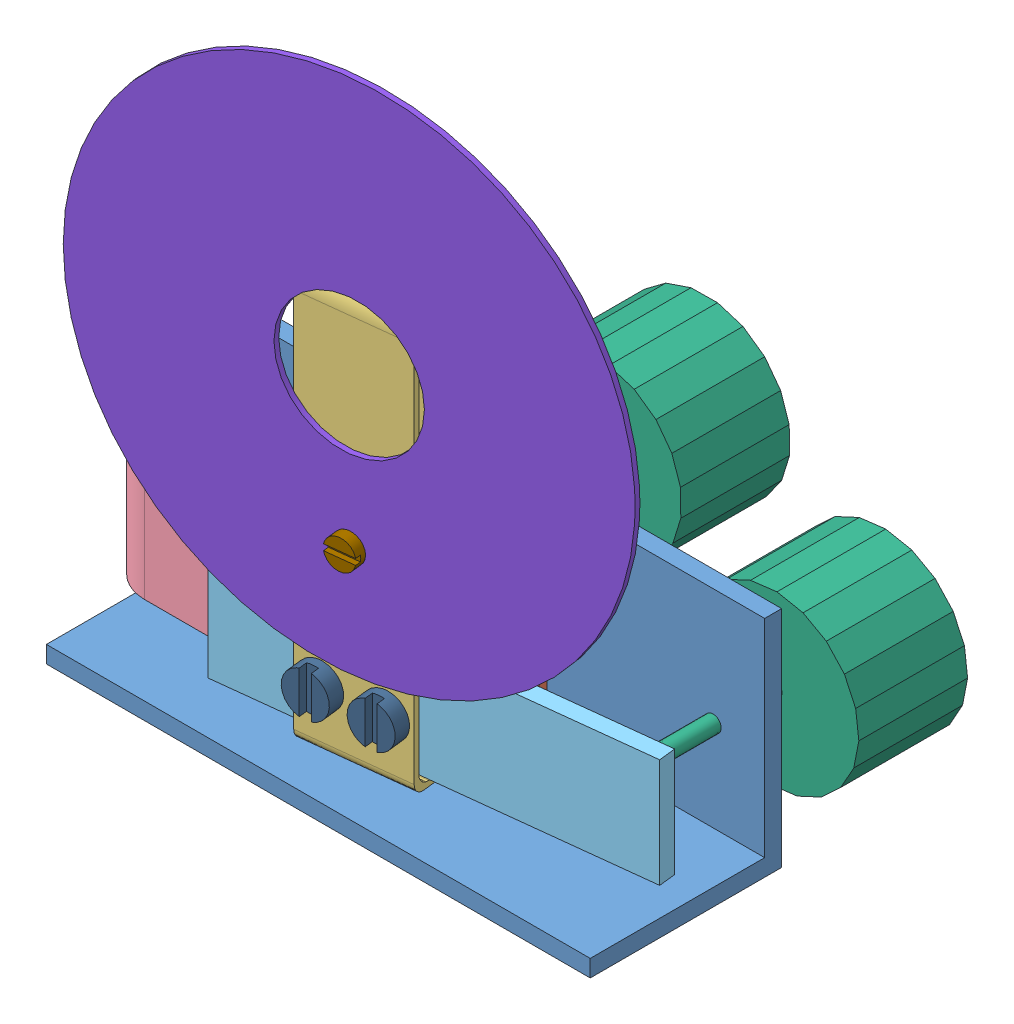
SolidWorks assembly Suporte do Hd, configuration Valor predeterminado. Lengths in mm.
Overall size (109.41 117.47 70.99).
25 component instances, 11 part files, 50 mates.
Components (placement in the parent):
- Base do divisor-1: Base do divisor [Default] at (-58.5949 -17.3298 117.599) size (100 41.23 35.2)
- Cantoneira pequena-2: Cantoneira pequena [Valor predeterminado] at (-18.5949 -13.8298 87.026) x (0 0 -1) z (1 0 0) size (16.5 16.5 20)
- Mola 1-1: Mola 1 [Valor predeterminado] at (-19.6607 -13.8298 89.0448) x (-0.113304 0 -0.99356) z (0.99356 0 -0.113304) size (25 80 20)
- Mola 2-1: Mola 2 [Valor predeterminado] at (-30.5949 8.7702 85.526) x (1 0 0) z (0 -1 0) size (30.12 25.83 20)
- Barra-1: Barra [Valor predeterminado] at (42.3181 -10.8298 102.9871) x (0.99356 0 -0.113304) z (0.113304 0 0.99356) size (75 20 3.12)
- Manipulo de tampinha de PET-1: Manipulo de tampinha de PET [Valor predeterminado] at (31.9104 -0.6809 54.3451) x (0.971217 0.238195 0) z (0 0 1) size (31.26 31.26 50)
- Manipulo de tampinha de PET-2: Manipulo de tampinha de PET [Valor predeterminado] at (-6.8829 13.8497 48.1396) x (0.879958 -0.475051 0) z (0 0 1) size (31.26 31.26 50)
- Porca M3-1: Porca M3 [Default] at (-6.8829 13.8497 94.3396) x (1 0 0) z (0 -1 0) size (6.52 3.8 6.82)
- HD-1: HD [Valor predeterminado] at (-6.8906 49.5081 112.7505) x (0.99356 -0.000072 -0.113304) z (0.113304 0 0.99356) size (95 95 1)
- Parafuso Padrao M3 10-1: Parafuso Padrao M3 10 [Default] at (-6.5526 22.0543 115.7314) x (-0.99356 0 0.113304) z (-0.113304 0 -0.99356) size (5.45 5.45 12)
- Porca M3-2: Porca M3 [Default] at (-7.0058 22.0543 111.7572) x (0.987162 0.113304 -0.112574) z (-0.112574 0.99356 0.012838) size (6.52 3.8 6.82)
- Parafuso Padrao M3 10-2: Parafuso Padrao M3 10 [Default] at (-16.0294 -6.3298 80.401) size (5.45 5.45 12)
- Parafuso Padrao M3 10-3: Parafuso Padrao M3 10 [Default] at (-1.1604 -6.3298 80.401) size (5.45 5.45 12)
- Porca M3-3: Porca M3 [Default] at (-16.0294 -6.3298 87.026) x (1 0 0) z (0 -1 0) size (6.52 3.8 6.82)
- Porca M3-4: Porca M3 [Default] at (-1.1604 -6.3298 87.026) x (1 0 0) z (0 -1 0) size (6.52 3.8 6.82)
- Parafuso Padrao M4-1: Parafuso Padrao M4 [Default] at (-40.5949 4.0287 82.401) x (-0.228935 0.973442 0) z (-0.973442 -0.228935 0) size (8 13 8)
- Parafuso Padrao M4-2: Parafuso Padrao M4 [Default] at (-40.5949 -7.6252 82.401) x (1 0 0) z (0 1 0) size (8 13 8)
- Parafuso Padrao M4-3: Parafuso Padrao M4 [Default] at (-12.557 -2.8298 113.3967) x (-0.99356 0 0.113304) z (0 1 0) size (8 13 8)
- Parafuso Padrao M4-4: Parafuso Padrao M4 [Default] at (-1.6819 -2.8298 112.1565) x (-0.99356 0 0.113304) z (0 1 0) size (8 13 8)
- Parafuso Padrao M4-5: Parafuso Padrao M4 [Default] at (-8.5921 -15.3298 97.8473) x (1 0 0) z (0 0 -1) size (8 13 8)
- Porca M4-1: Porca M4 [Default] at (-40.5949 4.0287 86.526) x (1 0 0) z (0 -1 0) size (7.78 3.12 8.95)
- Porca M4-2: Porca M4 [Default] at (-8.5921 -12.8298 97.8473) size (7.78 3.12 8.95)
- Porca M4-3: Porca M4 [Default] at (-13.3784 -2.8298 106.1934) x (0.987162 -0.113304 -0.112574) z (-0.112574 -0.99356 0.012838) size (7.78 3.12 8.95)
- Porca M4-4: Porca M4 [Default] at (-2.5033 -2.8298 104.9532) x (0.987162 -0.113304 -0.112574) z (-0.112574 -0.99356 0.012838) size (7.78 3.12 8.95)
- Porca M4-5: Porca M4 [Default] at (-40.5949 -7.6252 89.651) x (1 0 0) z (0 1 0) size (7.78 3.12 8.95)
Mates (geometry in assembly coordinates):
- Coincidente1: coincident anti-aligned: plane of Base do divisor-1 through (41.4051 -17.3298 85.526) normal (0 0 1); plane of Cantoneira pequena-2 through (1.4051 -13.8298 85.526) normal (0 0 -1)
- Distância1: distance = 2 mm anti-aligned: plane of Base do divisor-1 through (41.4051 -17.3298 117.599) normal (0 1 0); plane of Cantoneira pequena-2 through (1.4051 -15.3298 102.026) normal (0 -1 0)
- Distância2: distance = 40 mm aligned: plane of Cantoneira pequena-2 through (1.4051 -13.8298 87.026) normal (1 0 0); plane of Base do divisor-1 through (41.4051 -17.3298 82.401) normal (1 0 0)
- Concêntrico1: concentric anti-aligned: cylinder of Cantoneira pequena-2 through (-8.5921 -23.8298 97.8473) axis (0 1 0) radius 2; cylinder of Mola 1-1 through (-8.5921 -3.8298 97.8473) axis (0 -1 0) radius 2
- Coincidente4: coincident anti-aligned: plane of Cantoneira pequena-2 through (1.4051 -13.8298 102.026) normal (0 1 0); plane of Mola 1-1 through (0.2105 -13.8298 86.7787) normal (0 -1 0)
- Coincidente5: coincident anti-aligned: plane of Base do divisor-1 through (41.4051 -17.3298 85.526) normal (0 0 1); plane of Mola 2-1 through (-30.5949 -11.2298 85.526) normal (0 0 -1)
- Coincidente6: coincident aligned: plane of Base do divisor-1 through (-58.5949 -17.3298 82.401) normal (-1 0 0); plane of Mola 2-1 through (-58.5949 -11.2298 93.526) normal (-1 0 0)
- Distância3: distance = 12 mm aligned: plane of Base do divisor-1 through (41.4051 20.7702 85.526) normal (0 1 0); plane of Mola 2-1 through (-33.556 8.7702 111.526) normal (0 1 0)
- Coincidente8: coincident anti-aligned: plane of Mola 1-1 through (2.9298 6.1702 110.6241) normal (-0.113304 0 -0.99356); plane of Barra-1 through (42.6722 -10.8298 106.092) normal (0.113304 0 0.99356)
- Distância4: distance = 2 mm anti-aligned: plane of Mola 1-1 through (0.2105 -12.8298 86.7787) normal (0 1 0); plane of Barra-1 through (42.6722 -10.8298 106.092) normal (0 -1 0)
- Distância5: distance = 15 mm aligned: plane of Barra-1 through (-31.8448 -10.8298 114.5898) normal (-0.99356 0 0.113304); plane of Mola 1-1 through (-18.1878 58.1702 101.9611) normal (-0.99356 0 0.113304)
- Coincidente11: coincident: line of Mola 2-1 through (-28.4705 -11.2298 111.0597) axis (0 1 0); plane of Barra-1 through (42.3181 -10.8298 102.9871) normal (-0.113304 0 -0.99356)
- Concêntrico2: concentric anti-aligned: cylinder of Base do divisor-1 through (31.9104 -0.6809 75.526) axis (0 0 1) radius 1.5; cylinder of Manipulo de tampinha de PET-1 through (31.9104 -0.6809 104.3451) axis (0 0 -1) radius 1.5
- Tangente2: tangent: plane of Barra-1 through (42.3181 -10.8298 102.9871) normal (-0.113304 0 -0.99356); circle of Manipulo de tampinha de PET-1
- Concêntrico3: concentric anti-aligned: cylinder of Base do divisor-1 through (-6.8829 13.8497 75.526) axis (0 0 1) radius 1.5; cylinder of Manipulo de tampinha de PET-2 through (-6.8829 13.8497 98.1396) axis (0 0 -1) radius 1.5
- Coincidente16: coincident aligned: plane of Manipulo de tampinha de PET-2 through (-6.8829 13.8497 98.1396) normal (0 0 1); plane of Porca M3-1 through (-6.8829 13.8497 98.1396) normal (0 0 1)
- Coincidente19: coincident anti-aligned: plane of Mola 1-1 through (3.0431 -13.8298 111.6177) normal (0.113304 0 0.99356); plane of HD-1 through (-6.8906 49.5081 112.7505) normal (-0.113304 0 -0.99356)
- Coincidente20: coincident aligned: circle of HD-1; cylinder of Parafuso Padrao M3 10-1 through (-7.9123 22.0543 103.8087) axis (0.113304 0 0.99356) radius 1.5
- Coincidente21: coincident anti-aligned: plane of HD-1 through (-6.7773 49.5081 113.7441) normal (0.113304 0 0.99356); plane of Parafuso Padrao M3 10-1 through (-6.7792 22.0543 113.7443) normal (-0.113304 0 -0.99356)
- Tangente5: tangent anti-aligned: plane of Mola 1-1 through (-5.4022 26.7898 112.5808) normal (-0.99356 0 0.113304); cylinder of Parafuso Padrao M3 10-1 through (-7.9123 22.0543 103.8087) axis (0.113304 0 0.99356) radius 1.5
- Concêntrico5: concentric anti-aligned: cylinder of Parafuso Padrao M3 10-1 through (-7.9123 22.0543 103.8087) axis (0.113304 0 0.99356) radius 1.5; cylinder of Porca M3-2 through (-7.0058 22.0543 111.7572) axis (-0.113304 0 -0.99356) radius 1.5
- Coincidente22: coincident anti-aligned: plane of Mola 1-1 through (2.9298 6.1702 110.6241) normal (-0.113304 0 -0.99356); plane of Porca M3-2 through (-3.7013 27.0481 111.3803) normal (0.113304 0 0.99356)
- Concêntrico6: concentric anti-aligned: cylinder of Base do divisor-1 through (-16.0294 -6.3298 75.526) axis (0 0 1) radius 1.5; cylinder of Parafuso Padrao M3 10-2 through (-16.0294 -6.3298 92.401) axis (0 0 -1) radius 1.5
- Coincidente23: coincident anti-aligned: plane of Base do divisor-1 through (41.4051 -17.3298 82.401) normal (0 0 -1); plane of Parafuso Padrao M3 10-2 through (-16.0294 -6.3298 82.401) normal (0 0 1)
- Concêntrico7: concentric anti-aligned: cylinder of Base do divisor-1 through (-1.1604 -6.3298 75.526) axis (0 0 1) radius 1.5; cylinder of Parafuso Padrao M3 10-3 through (-1.1604 -6.3298 92.401) axis (0 0 -1) radius 1.5
- Coincidente24: coincident anti-aligned: plane of Base do divisor-1 through (41.4051 -17.3298 82.401) normal (0 0 -1); plane of Parafuso Padrao M3 10-3 through (-1.1604 -6.3298 82.401) normal (0 0 1)
- Concêntrico8: concentric anti-aligned: cylinder of Parafuso Padrao M3 10-2 through (-16.0294 -6.3298 92.401) axis (0 0 -1) radius 1.5; cylinder of Porca M3-3 through (-16.0294 -6.3298 87.026) axis (0 0 1) radius 1.5
- Coincidente25: coincident anti-aligned: plane of Cantoneira pequena-2 through (1.4051 -13.8298 87.026) normal (0 0 1); plane of Porca M3-3 through (-12.1591 -10.9146 87.026) normal (0 0 -1)
- Concêntrico9: concentric anti-aligned: cylinder of Parafuso Padrao M3 10-3 through (-1.1604 -6.3298 92.401) axis (0 0 -1) radius 1.5; cylinder of Porca M3-4 through (-1.1604 -6.3298 87.026) axis (0 0 1) radius 1.5
- Coincidente26: coincident anti-aligned: plane of Cantoneira pequena-2 through (1.4051 -13.8298 87.026) normal (0 0 1); plane of Porca M3-4 through (2.7099 -10.9146 87.026) normal (0 0 -1)
- Concêntrico10: concentric anti-aligned: cylinder of Base do divisor-1 through (-40.5949 4.0287 75.526) axis (0 0 1) radius 2; cylinder of Parafuso Padrao M4-1 through (-40.5949 4.0287 92.401) axis (0 0 -1) radius 2
- Coincidente27: coincident anti-aligned: plane of Base do divisor-1 through (41.4051 -17.3298 82.401) normal (0 0 -1); plane of Parafuso Padrao M4-1 through (-40.5949 4.0287 82.401) normal (0 0 1)
- Concêntrico11: concentric anti-aligned: cylinder of Base do divisor-1 through (-40.5949 -7.6252 75.526) axis (0 0 1) radius 2; cylinder of Parafuso Padrao M4-2 through (-40.5949 -7.6252 92.401) axis (0 0 -1) radius 2
- Coincidente28: coincident anti-aligned: plane of Base do divisor-1 through (41.4051 -17.3298 82.401) normal (0 0 -1); plane of Parafuso Padrao M4-2 through (-40.5949 -7.6252 82.401) normal (0 0 1)
- Concêntrico12: concentric anti-aligned: cylinder of Mola 1-1 through (-11.5373 -2.8298 122.3387) axis (-0.113304 0 -0.99356) radius 2; cylinder of Parafuso Padrao M4-3 through (-13.69 -2.8298 103.4611) axis (0.113304 0 0.99356) radius 2
- Coincidente29: coincident anti-aligned: plane of Mola 1-1 through (3.0431 -13.8298 111.6177) normal (0.113304 0 0.99356); plane of Parafuso Padrao M4-3 through (-12.557 -2.8298 113.3967) normal (-0.113304 0 -0.99356)
- Concêntrico13: concentric anti-aligned: cylinder of Mola 1-1 through (-0.6621 -2.8298 121.0986) axis (-0.113304 0 -0.99356) radius 2; cylinder of Parafuso Padrao M4-4 through (-2.8149 -2.8298 102.2209) axis (0.113304 0 0.99356) radius 2
- Coincidente30: coincident anti-aligned: plane of Mola 1-1 through (3.0431 -13.8298 111.6177) normal (0.113304 0 0.99356); plane of Parafuso Padrao M4-4 through (-1.6819 -2.8298 112.1565) normal (-0.113304 0 -0.99356)
- Concêntrico14: concentric anti-aligned: cylinder of Cantoneira pequena-2 through (-8.5921 -23.8298 97.8473) axis (0 1 0) radius 2; cylinder of Parafuso Padrao M4-5 through (-8.5921 -5.3298 97.8473) axis (0 -1 0) radius 2
- Coincidente31: coincident anti-aligned: plane of Cantoneira pequena-2 through (1.4051 -15.3298 102.026) normal (0 -1 0); plane of Parafuso Padrao M4-5 through (-8.5921 -15.3298 97.8473) normal (0 1 0)
- Concêntrico15: concentric anti-aligned: cylinder of Parafuso Padrao M4-3 through (-13.69 -2.8298 103.4611) axis (0.113304 0 0.99356) radius 2; cylinder of Porca M4-3 through (-13.0244 -2.8298 109.2983) axis (-0.113304 0 -0.99356) radius 2
- Concêntrico16: concentric anti-aligned: cylinder of Parafuso Padrao M4-4 through (-2.8149 -2.8298 102.2209) axis (0.113304 0 0.99356) radius 2; cylinder of Porca M4-4 through (-2.1492 -2.8298 108.0581) axis (-0.113304 0 -0.99356) radius 2
- Coincidente32: coincident anti-aligned: plane of Barra-1 through (42.3181 -10.8298 102.9871) normal (-0.113304 0 -0.99356); plane of Porca M4-4 through (1.4423 -5.4668 107.6485) normal (0.113304 0 0.99356)
- Concêntrico17: concentric aligned: cylinder of Parafuso Padrao M4-5 through (-8.5921 -5.3298 97.8473) axis (0 -1 0) radius 2; cylinder of Porca M4-2 through (-8.5921 -9.7048 97.8473) axis (0 -1 0) radius 2
- Coincidente34: coincident anti-aligned: plane of Mola 1-1 through (0.2105 -12.8298 86.7787) normal (0 1 0); plane of Porca M4-2 through (-4.7017 -12.8298 100.0578) normal (0 -1 0)
- Coincidente35: coincident anti-aligned: plane of Barra-1 through (42.3181 -10.8298 102.9871) normal (-0.113304 0 -0.99356); plane of Porca M4-3 through (-9.4328 -5.4668 108.8887) normal (0.113304 0 0.99356)
- Coincidente36: coincident anti-aligned: cylinder of Parafuso Padrao M4-1 through (-40.5949 4.0287 92.401) axis (0 0 -1) radius 2; circle of Porca M4-1
- Coincidente37: coincident anti-aligned: plane of Mola 2-1 through (-30.5949 -11.2298 86.526) normal (0 0 1); plane of Porca M4-1 through (-36.7045 1.8182 86.526) normal (0 0 -1)
- Concêntrico18: concentric anti-aligned: cylinder of Parafuso Padrao M4-2 through (-40.5949 -7.6252 92.401) axis (0 0 -1) radius 2; cylinder of Porca M4-5 through (-40.5949 -7.6252 86.526) axis (0 0 1) radius 2
- Coincidente38: coincident anti-aligned: plane of Mola 2-1 through (-30.5949 -11.2298 86.526) normal (0 0 1); plane of Porca M4-5 through (-36.7045 -5.4148 86.526) normal (0 0 -1)
